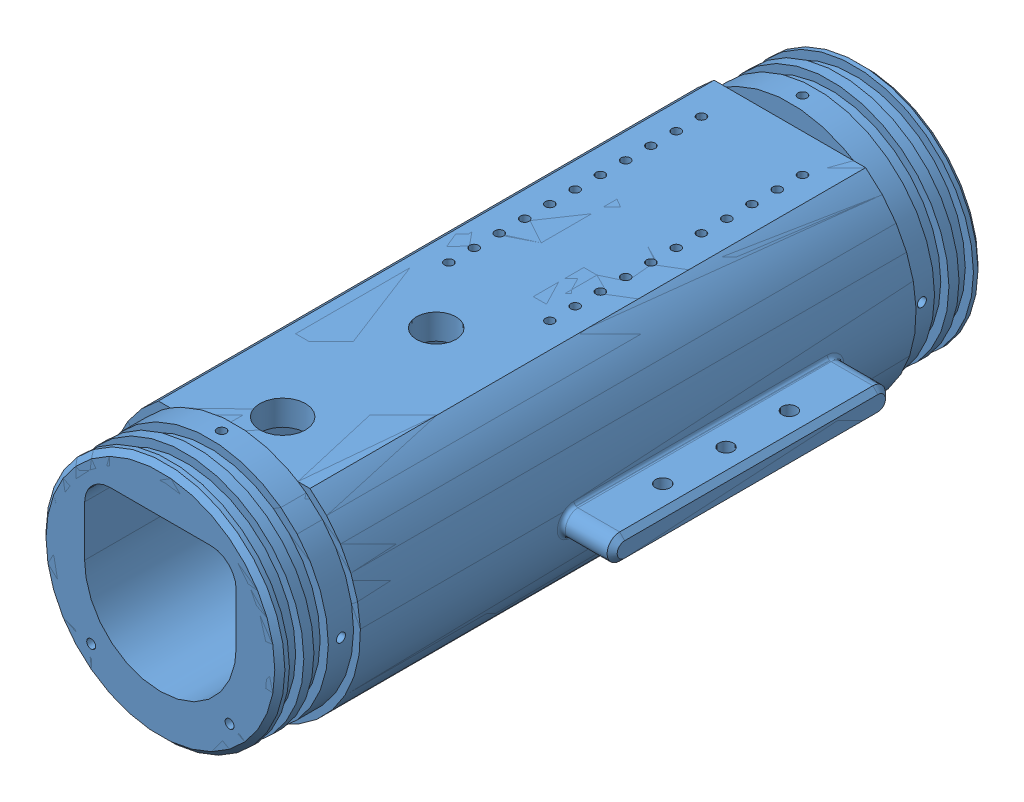
SolidWorks assembly Assem1, configuration Default. Lengths in mm.
Overall size (88.9 61.78 176.78).
2 component instances, 1 part files, 2 mates.
Components (placement in the parent):
- EXK-02-0017-1: EXK-02-0017 [Weight2] at origin size (88.9 61.78 176.78)
- EXK-02-0017-2: EXK-02-0017 [Default] at origin size (88.9 61.78 176.78)
Mates (geometry in assembly coordinates):
- Coincident1: coordinate: point of EXK-02-0017-1
- Coincident2: coordinate: unknown of EXK-02-0017-2
